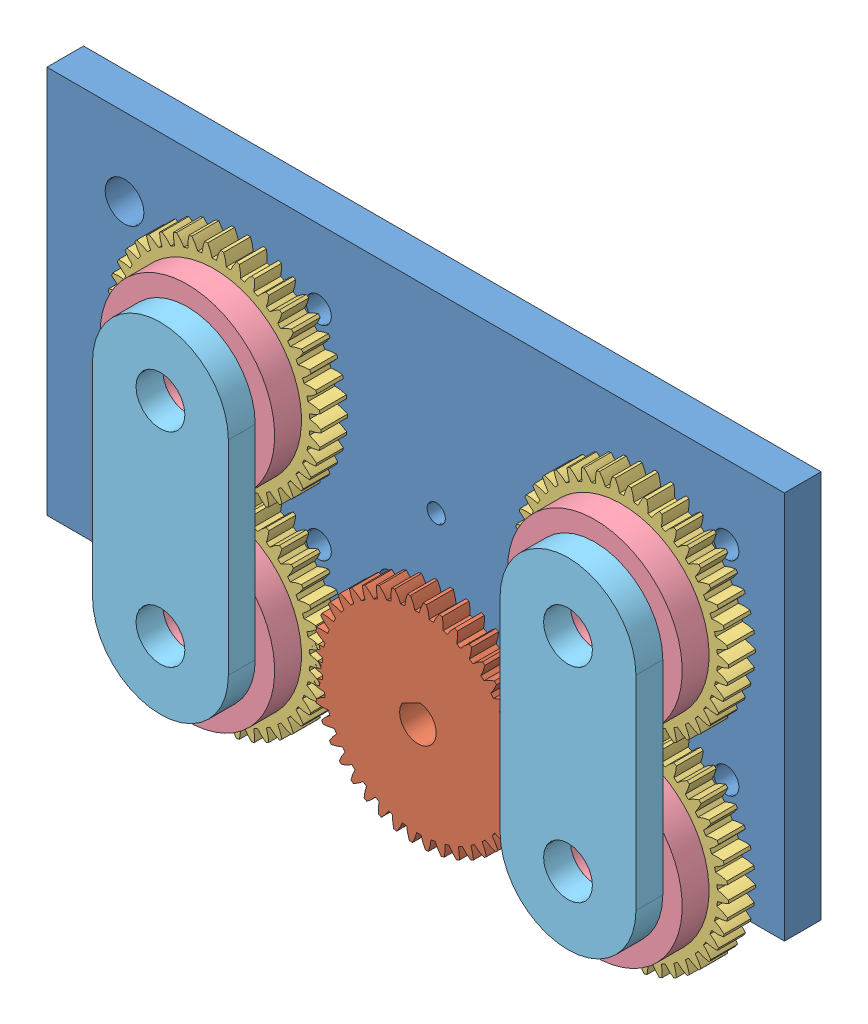
SolidWorks assembly wire feeder asm, configuration Default. Lengths in mm.
Overall size (122.24 75.14 29.92).
13 component instances, 6 part files, 34 mates.
Components (placement in the parent):
- wire feeder mounting plate-1: wire feeder mounting plate [Default] at (19.6084 25.137 140.1005) size (120.65 63.5 5.99)
- gearmotor gear-9: gearmotor gear [Inch - Spur gear 32DP 42T 20PA .173FW ---S42N3.0H2.0L0.03125N] at (91.0459 36.8576 156.8391) x (0 0 -1) z (0.896843 0.442349 0) size (4.39 34.86 34.92)
- 8mm gear-5: 8mm gear [Inch - Spur gear 32DP 42T 20PA .173FW ---S42N3.0H2.0L0.03125N] at (57.7084 70.2078 152.4449) x (0 0 1) z (-1 0 0) size (4.39 34.86 34.92)
- 8mm gear-6: 8mm gear [Inch - Spur gear 32DP 42T 20PA .173FW ---S42N3.0H2.0L0.03125N] at (124.3834 70.2078 152.4449) x (0 0 1) z (-1 0 0) size (4.39 34.86 34.92)
- 8mm gear-7: 8mm gear [Inch - Spur gear 32DP 42T 20PA .173FW ---S42N3.0H2.0L0.03125N] at (57.7084 36.8576 152.4449) x (0 0 1) z (-1 0 0) size (4.39 34.86 34.92)
- 8mm gear-8: 8mm gear [Inch - Spur gear 32DP 42T 20PA .173FW ---S42N3.0H2.0L0.03125N] at (124.3834 36.8576 152.4449) x (0 0 1) z (-1 0 0) size (4.39 34.86 34.92)
- feeder pulley-1: feeder pulley [Default] at (124.3834 36.8576 156.8391) size (28.57 28.57 4.39)
- feeder pulley-2: feeder pulley [Default] at (124.3834 70.2078 156.8391) size (28.57 28.57 4.39)
- feeder pulley-3: feeder pulley [Default] at (57.7084 70.2078 156.8391) size (28.57 28.57 4.39)
- feeder pulley-4: feeder pulley [Default] at (57.7084 36.8576 156.8391) size (28.57 28.57 4.39)
- shaft aligner-1: shaft aligner [Default] at (57.7084 70.2078 161.2333) x (0 -1 0) z (0 0 1) size (55.58 22.23 4.39)
- shaft aligner-2: shaft aligner [Default] at (124.3834 70.2078 161.2333) x (0 -1 0) z (0 0 1) size (55.58 22.23 4.39)
- v2 arcyrlic spacer-1: v2 arcyrlic spacer [Default] at (48.1834 60.6828 135.7063) size (19.05 19.05 4.39)
Mates (geometry in assembly coordinates):
- Concentric11: concentric aligned: cylinder of wire feeder mounting plate-1 through (91.0459 36.8576 146.0949) axis (0 0 -1) radius 6.5; cylinder of gearmotor gear-9 through (91.0459 36.8576 159.8109) axis (0 0 -1) radius 3
- Distance3: distance = 6.35 mm anti-aligned: plane of gearmotor gear-9 through (91.0459 36.8576 152.4449) normal (0 0 -1); plane of wire feeder mounting plate-1 through (19.6084 25.137 146.0949) normal (0 0 1)
- Coincident14: coincident aligned: plane of gearmotor gear-9 through (91.0459 36.8576 156.8391) normal (0 0 1); plane of 8mm gear-5 through (57.7084 70.2078 156.8391) normal (0 0 1)
- Concentric12: concentric anti-aligned: cylinder of wire feeder mounting plate-1 through (57.7084 70.2078 146.0949) axis (0 0 -1) radius 4; cylinder of 8mm gear-5 through (57.7084 70.2078 149.4731) axis (0 0 1) radius 4
- Concentric13: concentric anti-aligned: cylinder of wire feeder mounting plate-1 through (124.3834 70.2078 146.0949) axis (0 0 -1) radius 4; cylinder of 8mm gear-6 through (124.3834 70.2078 149.4731) axis (0 0 1) radius 4
- Coincident15: coincident aligned: plane of 8mm gear-5 through (57.7084 70.2078 156.8391) normal (0 0 1); plane of 8mm gear-6 through (124.3834 70.2078 156.8391) normal (0 0 1)
- Concentric14: concentric anti-aligned: cylinder of wire feeder mounting plate-1 through (57.7084 36.8576 146.0949) axis (0 0 -1) radius 4; cylinder of 8mm gear-7 through (57.7084 36.8576 149.4731) axis (0 0 1) radius 4
- Coincident16: coincident anti-aligned: circle of gearmotor gear-9; plane of 8mm gear-7 through (57.7084 36.8576 156.8391) normal (0 0 1)
- Concentric15: concentric anti-aligned: cylinder of wire feeder mounting plate-1 through (124.3834 36.8576 146.0949) axis (0 0 -1) radius 4; cylinder of 8mm gear-8 through (124.3834 36.8576 149.4731) axis (0 0 1) radius 4
- Coincident17: coincident aligned: plane of 8mm gear-7 through (57.7084 36.8576 156.8391) normal (0 0 1); plane of 8mm gear-8 through (124.3834 36.8576 156.8391) normal (0 0 1)
- Concentric16: concentric anti-aligned: cylinder of 8mm gear-5 through (57.7084 70.2078 149.4731) axis (0 0 1) radius 4; cylinder of feeder pulley-3 through (57.7084 70.2078 161.2333) axis (0 0 -1) radius 4
- Coincident18: coincident anti-aligned: plane of 8mm gear-5 through (57.7084 70.2078 156.8391) normal (0 0 1); plane of feeder pulley-3 through (57.7084 70.2078 156.8391) normal (0 0 -1)
- Concentric17: concentric anti-aligned: cylinder of 8mm gear-7 through (57.7084 36.8576 149.4731) axis (0 0 1) radius 4; cylinder of feeder pulley-4 through (57.7084 36.8576 161.2333) axis (0 0 -1) radius 4
- Coincident19: coincident anti-aligned: plane of 8mm gear-7 through (57.7084 36.8576 156.8391) normal (0 0 1); plane of feeder pulley-4 through (57.7084 36.8576 156.8391) normal (0 0 -1)
- Coincident20: coincident anti-aligned: plane of 8mm gear-8 through (124.3834 36.8576 156.8391) normal (0 0 1); plane of feeder pulley-1 through (124.3834 36.8576 156.8391) normal (0 0 -1)
- Concentric18: concentric anti-aligned: cylinder of 8mm gear-8 through (124.3834 36.8576 149.4731) axis (0 0 1) radius 4; cylinder of feeder pulley-1 through (124.3834 36.8576 161.2333) axis (0 0 -1) radius 4
- Concentric19: concentric anti-aligned: cylinder of 8mm gear-6 through (124.3834 70.2078 149.4731) axis (0 0 1) radius 4; cylinder of feeder pulley-2 through (124.3834 70.2078 161.2333) axis (0 0 -1) radius 4
- Coincident21: coincident aligned: plane of feeder pulley-2 through (124.3834 70.2078 161.2333) normal (0 0 1); plane of feeder pulley-3 through (57.7084 70.2078 161.2333) normal (0 0 1)
- Concentric20: concentric anti-aligned: cylinder of 8mm gear-7 through (57.7084 46.3826 149.4731) axis (0 0 1) radius 1.1303; cylinder of feeder pulley-4 through (57.7084 46.3826 161.2333) axis (0 0 -1) radius 1.4224
- Concentric21: concentric anti-aligned: cylinder of 8mm gear-8 through (115.3246 39.801 149.4731) axis (0 0 1) radius 1.1303; cylinder of feeder pulley-1 through (115.3246 39.801 161.2333) axis (0 0 -1) radius 1.4224
- Concentric22: concentric anti-aligned: cylinder of 8mm gear-5 through (48.6496 73.1512 149.4731) axis (0 0 1) radius 1.1303; cylinder of feeder pulley-3 through (48.6496 73.1512 161.2333) axis (0 0 -1) radius 1.4224
- Concentric23: concentric anti-aligned: cylinder of 8mm gear-6 through (115.3246 73.1512 149.4731) axis (0 0 1) radius 1.1303; cylinder of feeder pulley-2 through (115.3246 73.1512 161.2333) axis (0 0 -1) radius 1.4224
- Concentric24: concentric aligned: cylinder of feeder pulley-3 through (57.7084 70.2078 161.2333) axis (0 0 -1) radius 4; cylinder of shaft aligner-1 through (57.7084 70.2078 165.6275) axis (0 0 -1) radius 4
- Coincident22: coincident anti-aligned: plane of feeder pulley-3 through (57.7084 70.2078 161.2333) normal (0 0 1); plane of shaft aligner-1 through (57.7084 70.2078 161.2333) normal (0 0 -1)
- Parallel1: parallel aligned: cylinder of feeder pulley-2 through (124.3834 70.2078 161.2333) axis (0 0 -1) radius 4; cylinder of shaft aligner-1 through (57.7084 36.8576 165.6275) axis (0 0 -1) radius 4
- Coincident23: coincident anti-aligned: plane of feeder pulley-4 through (57.7084 36.8576 161.2333) normal (0 0 1); plane of shaft aligner-2 through (124.3834 70.2078 161.2333) normal (0 0 -1)
- Concentric26: concentric aligned: cylinder of feeder pulley-1 through (124.3834 36.8576 161.2333) axis (0 0 -1) radius 4; cylinder of shaft aligner-2 through (124.3834 36.8576 165.6275) axis (0 0 -1) radius 4
- Parallel2: parallel aligned: cylinder of feeder pulley-4 through (57.7084 36.8576 161.2333) axis (0 0 -1) radius 4; cylinder of shaft aligner-2 through (124.3834 70.2078 165.6275) axis (0 0 -1) radius 4
- Concentric28: concentric aligned: cylinder of feeder pulley-4 through (57.7084 36.8576 161.2333) axis (0 0 -1) radius 4; cylinder of shaft aligner-1 through (57.7084 36.8576 165.6275) axis (0 0 -1) radius 4
- Concentric29: concentric aligned: cylinder of feeder pulley-2 through (124.3834 70.2078 161.2333) axis (0 0 -1) radius 4; cylinder of shaft aligner-2 through (124.3834 70.2078 165.6275) axis (0 0 -1) radius 4
- Coincident24: coincident: plane of wire feeder mounting plate-1 through (19.6084 25.137 140.1005) normal (0 0 -1); plane of v2 arcyrlic spacer-1 through (48.1834 60.6828 140.1005) normal (0 0 1)
- Coincident25: coincident: plane of wire feeder mounting plate-1 through (19.6084 25.137 140.1005) normal (0 0 -1); plane of v2 arcyrlic spacer-1 through (48.1834 60.6828 140.1005) normal (0 0 1)
- Concentric30: concentric: cylinder of wire feeder mounting plate-1 through (64.0584 63.8578 146.0949) axis (0 0 -1) radius 2.0828; cylinder of v2 arcyrlic spacer-1 through (64.0584 63.8578 140.1005) axis (0 0 -1) radius 2.0828
- Concentric31: concentric aligned: cylinder of wire feeder mounting plate-1 through (57.7084 70.2078 146.0949) axis (0 0 -1) radius 4; cylinder of v2 arcyrlic spacer-1 through (57.7084 70.2078 140.1005) axis (0 0 -1) radius 4
